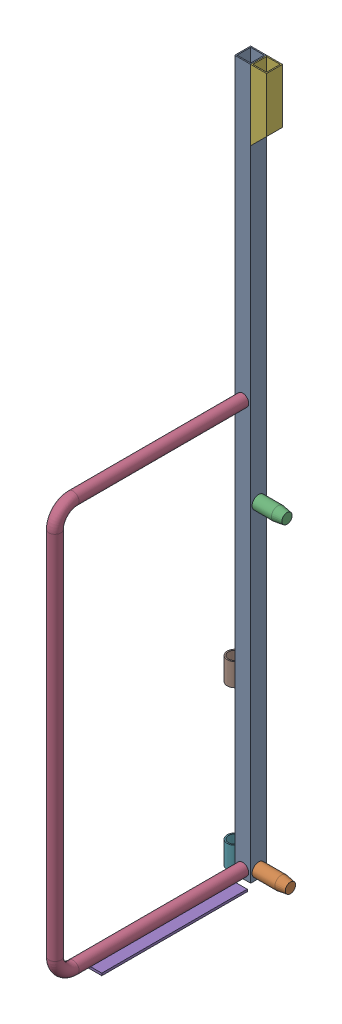
SolidWorks assembly FE-00002-L_ASM, configuration Default. Lengths in mm.
Overall size (175.51 1981.23 585.85).
8 component instances, 7 part files, 0 mates.
Components (placement in the parent):
- FE-00002-05-1: FE-00002-05 [Default] at origin size (44.45 1981.2 44.45)
- FE-00002-01-1: FE-00002-01 [Default] at (3.175 22.225 -22.225) size (130.18 36.51 36.51)
- FE-00002-02-1: FE-00002-02 [Default] at (3.175 911.225 -22.225) size (120.65 36.51 36.51)
- FE-00002-06-1: FE-00002-06 [Default] at (22.225 23.0188 0) x (1 0 0) z (0 0 -1) size (33.4 1168.46 541.4)
- FE-00002-07-1: FE-00002-07 [Default] at (60.325 6.3182 25.4) x (0 0 1) z (1 0 0) size (406.4 6.35 76.2)
- FE-00002-03-1: FE-00002-03 [Default] at (44.45 1981.2 0) x (0 0 -1) z (-1 0 0) size (44.45 196.85 44.45)
- FE-00002-09-1: FE-00002-09 [Default] at (-21.082 31.75 -21.1582) size (42.16 63.5 42.16)
- FE-00002-09-2: FE-00002-09 [Default] at (-21.082 476.25 -21.1582) size (42.16 63.5 42.16)
